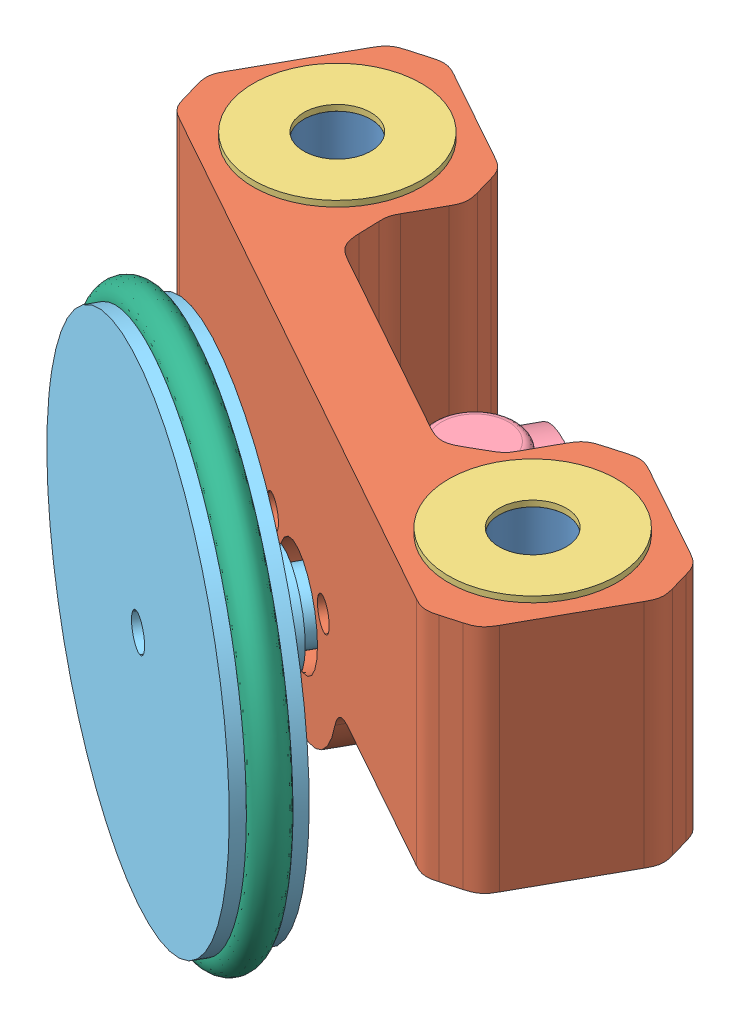
SolidWorks assembly Systeme Encodeurs Partie Mobile, configuration Défaut. Lengths in mm.
Overall size (87.47 73.75 71.62).
9 component instances, 6 part files, 56 mates.
Components (placement in the parent):
- Roulement linéaire-1: Roulement linéaire [Défaut] at (-9.7273 27.4164 48.8402) x (-0.971705 0 -0.236196) z (0 -1 0) size (15 15 24)
- Roulement linéaire-2: Roulement linéaire [Défaut] at (42.7043 27.4164 78.011) x (0.932325 0 -0.361623) z (0 -1 0) size (15 15 24)
- Support Encodeurs-1: Support Encodeurs [Défaut] at (16.4885 2.4164 63.4256) x (0.873859 0 0.486179) z (-0.486179 0 0.873859) size (84.1 37.8 24.1)
- Rondelle M8-1: Rondelle M8 [Défaut] at (-9.7273 27.4164 48.8402) x (-0.837169 0 -0.546944) z (0 1 0) size (20 20 0.7)
- Rondelle M8-2: Rondelle M8 [Défaut] at (42.7043 27.4164 78.011) x (1 0 0) z (0 1 0) size (20 20 0.7)
- Codeurs Kuebler D24-2: Codeurs Kuebler D24 [Défaut] at (22.0795 1.9164 53.3762) x (-0.873859 0 -0.486179) z (-0.486179 0 0.873859) size (24 26 30.5)
- Assemblage Roue Codeuse-1: Assemblage Roue Codeuse [Défaut] at (55.0797 -20.031 76.4776) x (-0.842662 0.264817 -0.468822) z (0.486179 0 -0.873859) size (60 60 17)
  - Roue folle D56 BRS-1: Roue folle D56 BRS [Défaut] at (44.4504 10.553 -33.3566) size (56 56 17)
  - Joint Torique D52 T4 BRS-1: Joint Torique D52 T4 BRS [Défaut] at (44.4504 10.553 -29.8566) size (60 60 4)
Mates (geometry in assembly coordinates):
- Coaxiale1: concentric: cylinder of ? through (-9.7273 63.6762 48.8402) axis (0 -1 0) radius 4; cylinder of Roulement linéaire-1 through (-9.7273 3.4164 48.8402) axis (0 1 0) radius 4
- Coaxiale4: concentric: cylinder of ? through (42.7043 63.6762 78.011) axis (0 -1 0) radius 4; cylinder of Roulement linéaire-2 through (42.7043 3.4164 78.011) axis (0 1 0) radius 4
- Coaxiale8: concentric anti-aligned: cylinder of Rondelle M8-1 through (-9.7273 26.6164 48.8402) axis (0 1 0) radius 4; cylinder of ? through (-9.7273 63.6762 48.8402) axis (0 -1 0) radius 4
- Coaxiale9: concentric: cylinder of ? through (42.7043 63.6762 78.011) axis (0 -1 0) radius 4; cylinder of Rondelle M8-2 through (42.7043 26.6164 78.011) axis (0 1 0) radius 4
- Coïncidente3: coincident anti-aligned: plane of Roulement linéaire-2 through (42.7043 27.4164 78.011) normal (0 1 0); plane of Rondelle M8-2 through (42.7043 27.4164 78.011) normal (0 -1 0)
- Coïncidente4: coincident anti-aligned: plane of Roulement linéaire-1 through (-9.7273 27.4164 48.8402) normal (0 1 0); plane of Rondelle M8-1 through (-9.7273 27.4164 48.8402) normal (0 -1 0)
- Coïncidente5: coincident anti-aligned: plane of Support Encodeurs-1 through (16.4885 27.4164 63.4256) normal (0 1 0); plane of Rondelle M8-1 through (-9.7273 27.4164 48.8402) normal (0 -1 0)
- Coïncidente6: coincident anti-aligned: plane of Support Encodeurs-1 through (16.4885 27.4164 63.4256) normal (0 1 0); plane of Rondelle M8-2 through (42.7043 27.4164 78.011) normal (0 -1 0)
- Coaxiale10: concentric: cylinder of Support Encodeurs-1 through (17.1967 11.4762 30.977) axis (-0.822784 0 -0.568354) radius 1.8; cylinder of ? through (12.6714 11.4762 27.851) axis (0.822784 0 0.568354) radius 1.8
- Coaxiale11: concentric: cylinder of Support Encodeurs-1 through (21.6266 24.9762 24.564) axis (-0.822784 0 -0.568354) radius 1.8; cylinder of ? through (17.1013 24.9762 21.4381) axis (0.822784 0 0.568354) radius 1.8
- Coaxiale12: concentric: cylinder of Support Encodeurs-1 through (12.7668 24.9762 37.3899) axis (-0.822784 0 -0.568354) radius 1.8; cylinder of ? through (8.2415 24.9762 34.264) axis (0.822784 0 0.568354) radius 1.8
- Coïncidente7: coincident: plane of Support Encodeurs-1 through (15.1398 20.4762 29.5561) normal (-0.822784 0 -0.568354); plane of ? through (15.1398 20.4762 29.5561) normal (0.822784 0 0.568354)
- Coaxiale14: concentric: cylinder of Support Encodeurs-1 through (21.6266 24.9762 24.564) axis (-0.822784 0 -0.568354) radius 1.8; cylinder of ? through (17.5127 24.9762 21.7222) axis (0.822784 0 0.568354) radius 1.8
- Coaxiale15: concentric: cylinder of Support Encodeurs-1 through (12.7668 24.9762 37.3899) axis (-0.822784 0 -0.568354) radius 1.8; cylinder of ? through (8.6529 24.9762 34.5482) axis (0.822784 0 0.568354) radius 1.8
- Coaxiale16: concentric: cylinder of Support Encodeurs-1 through (17.1967 11.4762 30.977) axis (-0.822784 0 -0.568354) radius 1.8; cylinder of ? through (13.0828 11.4762 28.1352) axis (0.822784 0 0.568354) radius 1.8
- Coïncidente8: coincident anti-aligned: plane of Support Encodeurs-1 through (43.861 27.4164 92.3867) normal (-0.486179 0 0.873859); plane of ? through (12.7668 24.9762 37.3899) normal (-0.822784 0 -0.568354)
- Coïncidente9: coincident anti-aligned: plane of Support Encodeurs-1 through (43.861 27.4164 92.3867) normal (-0.486179 0 0.873859); plane of ? through (21.6266 24.9762 24.564) normal (-0.822784 0 -0.568354)
- Coïncidente10: coincident anti-aligned: plane of Support Encodeurs-1 through (43.861 27.4164 92.3867) normal (-0.486179 0 0.873859); plane of ? through (17.1967 11.4762 30.977) normal (-0.822784 0 -0.568354)
- Coaxiale19: concentric: cylinder of ? through (42.7043 63.6762 78.011) axis (0 -1 0) radius 4; circle of ?
- Coaxiale20: concentric: cylinder of ? through (-9.7273 63.6762 48.8402) axis (0 -1 0) radius 4; circle of ?
- Coïncidente11: coincident: plane of ? through (-9.7273 63.6762 48.8402) normal (0 1 0); plane of ? through (16.4885 63.6762 63.4256) normal (0 -1 0)
- Coaxiale21: concentric: cylinder of ? through (-9.7273 63.6762 48.8402) axis (0 -1 0) radius 4; cylinder of ? through (-9.7273 63.6762 48.8402) axis (0 -1 0) radius 4
- Coïncidente14: coincident: plane of ? through (16.4885 63.6762 63.4256) normal (0 -1 0); plane of ? through (42.7043 63.6762 78.011) normal (0 1 0)
- Coaxiale23: concentric: cylinder of ? through (-14.4934 59.1762 59.978) axis (0.486179 0 -0.873859) radius 2.75; circle of ?
- Coïncidente13: coincident: plane of ? through (10.6543 66.6762 73.9119) normal (-0.486179 0 0.873859); plane of ? through (-14.4691 59.1762 59.9343) normal (-0.486179 0 0.873859)
- Coaxiale24: concentric: cylinder of ? through (18.4953 57.1762 101.7576) axis (0.769806 0 -0.638278) radius 2.75; cylinder of ? through (43.1676 57.1762 81.3008) axis (-0.769806 0 0.638278) radius 2.75
- Coaxiale26: concentric: cylinder of ? through (-18.2056 57.1762 57.4937) axis (0.769806 0 -0.638278) radius 2.75; cylinder of ? through (6.4667 57.1762 37.0369) axis (-0.769806 0 0.638278) radius 2.75
- Coïncidente16: coincident: plane of ?; plane of ? through (0.3082 57.1762 42.1432) normal (-0.769806 0 0.638278)
- Coaxiale27: concentric: cylinder of ? through (35.7535 59.1762 87.9332) axis (0.486179 0 -0.873859) radius 2.75; cylinder of ? through (39.6672 59.1762 80.8987) axis (-0.486179 0 0.873859) radius 2.75
- Coïncidente17: coincident: plane of ? through (10.6543 66.6762 73.9119) normal (-0.486179 0 0.873859); plane of ? through (35.7778 59.1762 87.8896) normal (-0.486179 0 0.873859)
- Coaxiale28: concentric: cylinder of ? through (18.0195 20.4762 31.5453) axis (-0.822784 0 -0.568354) radius 2.5; cylinder of ? through (29.1271 20.4762 39.2181) axis (-0.822784 0 -0.568354) radius 2.1
- Coïncidente18: coincident: plane of ? through (15.1398 20.4762 29.5561) normal (0.822784 0 0.568354); plane of ?
- Coaxiale29: concentric anti-aligned: cylinder of Support Encodeurs-1 through (10.63 -7.0836 73.9556) axis (0.486179 0 -0.873859) radius 1.8; cylinder of Codeurs Kuebler D24-2 through (13.5714 -7.0836 68.6688) axis (-0.486179 0 0.873859) radius 1.8
- Coaxiale30: concentric anti-aligned: cylinder of Support Encodeurs-1 through (3.819 6.4164 70.1662) axis (0.486179 0 -0.873859) radius 1.8; cylinder of Codeurs Kuebler D24-2 through (6.7603 6.4164 64.8794) axis (-0.486179 0 0.873859) radius 1.8
- Coïncidente19: coincident anti-aligned: plane of Support Encodeurs-1 through (12.1129 2.4164 71.2903) normal (0.486179 0 -0.873859); plane of Codeurs Kuebler D24-2 through (12.1129 1.9164 71.2903) normal (-0.486179 0 0.873859)
- Coaxiale31: concentric: cylinder of ? through (-32.905 9.6159 81.0706) axis (0.995895 0 -0.090519) radius 2.1; cylinder of Codeurs Kuebler D24-2 through (10.4112 1.9164 74.3488) axis (0.486179 0 -0.873859) radius 2.5
- Coïncidente20: coincident: plane of ? through (-15.9748 9.6159 79.5318) normal (0.995895 0 -0.090519); plane of Codeurs Kuebler D24-2 through (12.1129 1.9164 71.2903) normal (-0.486179 0 0.873859)
- Coaxiale32: concentric: cylinder of ? through (-9.7273 63.6762 48.8402) axis (0 -1 0) radius 4; cylinder of ? through (-9.7273 -0.3238 48.8402) axis (0 -1 0) radius 4
- Coaxiale33: concentric: cylinder of ? through (42.7043 63.6762 78.011) axis (0 -1 0) radius 4; cylinder of ? through (42.7043 -0.3238 78.011) axis (0 -1 0) radius 4
- Coïncidente21: coincident: plane of ? through (-9.7273 -8.3238 48.8402) normal (0 -1 0); plane of ? through (-9.7273 -8.3238 48.8402) normal (0 1 0)
- Coaxiale34: concentric: cylinder of ? through (53.1914 -4.8238 83.8456) axis (-0.873859 0 -0.486179) radius 2.75; cylinder of ? through (-13.2227 -4.8238 46.8955) axis (-0.873859 0 -0.486179) radius 2.75
- Coïncidente22: coincident: plane of ? through (-20.2136 -0.3238 43.0061) normal (-0.873859 0 -0.486179); plane of ? through (-20.2136 -4.8238 43.0061) normal (-0.873859 0 -0.486179)
- Coaxiale35: concentric: cylinder of ? through (-20.2145 -4.8238 43.0056) axis (0.873859 0 0.486179) radius 2.75; cylinder of ? through (46.1997 -4.8238 79.9557) axis (0.873859 0 0.486179) radius 2.75
- Coïncidente23: coincident: plane of ? through (53.1906 -0.3238 83.8451) normal (0.873859 0 0.486179); plane of ? through (53.1906 -4.8238 83.8451) normal (0.873859 0 0.486179)
- Coïncidente24: coincident: plane of ?; plane of ? through (37.0092 57.1762 86.407) normal (-0.769806 0 0.638278)
- Coaxiale36: concentric: cylinder of ? through (42.7043 63.6762 78.011) axis (0 -1 0) radius 4; cylinder of ? through (42.7043 63.6762 78.011) axis (0 -1 0) radius 4
- Coaxiale37: concentric: cylinder of ? through (-7.7763 -1.8238 35.0492) axis (0 -1 0) radius 2.75; cylinder of ? through (-7.7763 -2.3238 35.0492) axis (0 -1 0) radius 2.75
- Coaxiale38: concentric: cylinder of ? through (53.3939 -1.8238 69.0817) axis (0 -1 0) radius 2.75; cylinder of ? through (53.3939 -2.3238 69.0817) axis (0 -1 0) radius 2.75
- Coaxiale39: concentric aligned: cylinder of Codeurs Kuebler D24-2 through (10.4112 1.9164 74.3488) axis (0.486179 0 -0.873859) radius 2.5; cylinder of Assemblage Roue Codeuse-1/Roue folle D46 BRS-1 through (3.8478 1.9164 86.1459) axis (0.486179 0 -0.873859) radius 2
- Coïncidente27: coincident anti-aligned: plane of Codeurs Kuebler D24-2 through (12.1129 1.9164 71.2903) normal (-0.486179 0 0.873859); plane of Assemblage Roue Codeuse-1/Roue folle D46 BRS-1 through (12.1129 1.9164 71.2903) normal (0.486179 0 -0.873859)
- Coaxiale40: concentric anti-aligned: cylinder of Roulement linéaire-1 through (-9.7273 3.4164 48.8402) axis (0 1 0) radius 7.5; cylinder of Support Encodeurs-1 through (-9.7273 27.4164 48.8402) axis (0 -1 0) radius 7.6
- Coaxiale41: concentric aligned: cylinder of Roulement linéaire-2 through (42.7043 3.4164 78.011) axis (0 1 0) radius 7.5; cylinder of Support Encodeurs-1 through (42.7043 3.4164 78.011) axis (0 1 0) radius 7.7
- Coïncidente28: coincident: plane of ? through (16.4885 -9.3238 63.4256) normal (0 -1 0); plane of ? through (-7.7763 -9.3238 35.0492) normal (0 1 0)
- Coïncidente29: coincident: plane of ? through (16.4885 -9.3238 63.4256) normal (0 -1 0); plane of ? through (53.3939 -9.3238 69.0817) normal (0 1 0)
- Tangent9: tangent: plane of ? through (16.4885 51.6762 63.4256) normal (0 -1 0); circle of ?
- Tangent10: tangent: plane of ? through (16.4885 51.6762 63.4256) normal (0 -1 0); circle of ?
